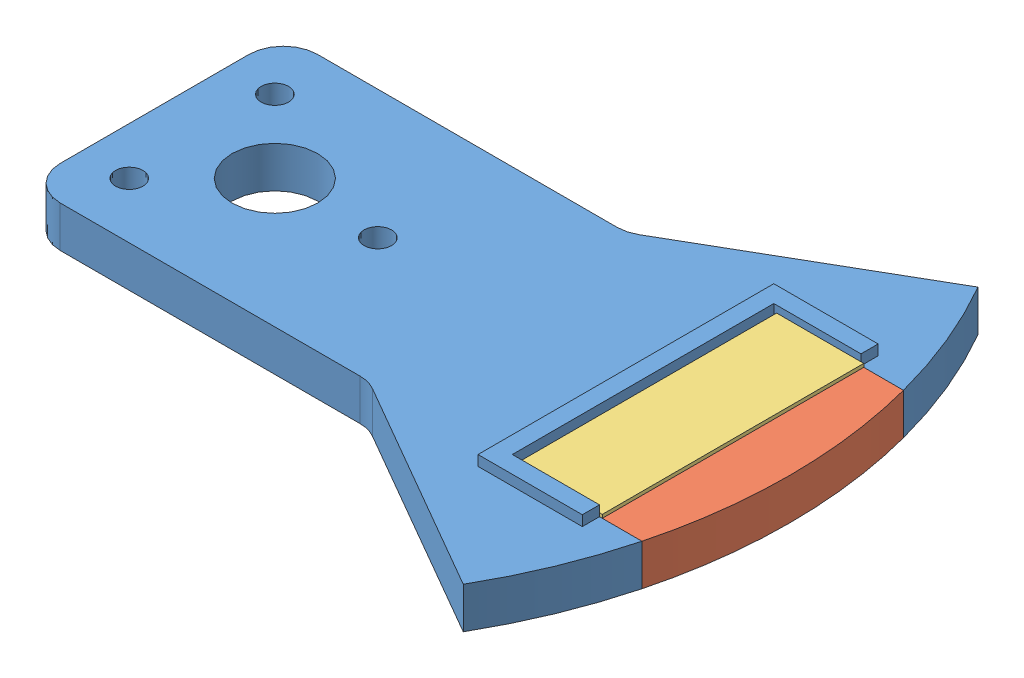
SolidWorks assembly Sector Module, configuration Default. Lengths in mm.
Overall size (185.05 15 150).
3 component instances, 3 part files, 5 mates.
Components (placement in the parent):
- Sector-1: Sector [Default] at (2.5872 99.2948 166.3147) size (180.13 15 150)
- Trapdoor-1: Trapdoor [Default] at (2.5872 99.2948 166.3147) size (42.7 12 76.2)
- Glass Slide-1: Glass Slide [Default] at (123.4019 111.2948 166.3147) x (0 0 -1) z (1 0 0) size (76.2 1 25.4)
Mates (geometry in assembly coordinates):
- Coincident1: coincident anti-aligned: plane of Sector-1 through (109.8872 99.2948 204.4147) normal (0 0 -1); plane of Trapdoor-1 through (2.5872 99.2948 204.4147) normal (0 0 1)
- Coincident3: coincident aligned: line of Sector-1 through (109.8872 99.2948 128.2147) axis (0 0 1); line of Trapdoor-1 through (109.8872 99.2948 128.2147) axis (0 0 1)
- LimitAngle1: limit planar angle = 0 rad anti-aligned: plane of Sector-1 through (109.8872 99.2948 128.2147) normal (1 0 0); plane of Trapdoor-1 through (109.8872 99.2948 166.3147) normal (-1 0 0)
- Coincident4: coincident anti-aligned: plane of Trapdoor-1; plane of Glass Slide-1 through (123.4019 111.2948 166.3147) normal (0 -1 0)
- Coincident5: coincident anti-aligned: plane of Sector-1 through (109.8872 99.2948 204.4147) normal (0 0 -1); plane of Glass Slide-1 through (110.7019 112.2948 204.4147) normal (0 0 1)
